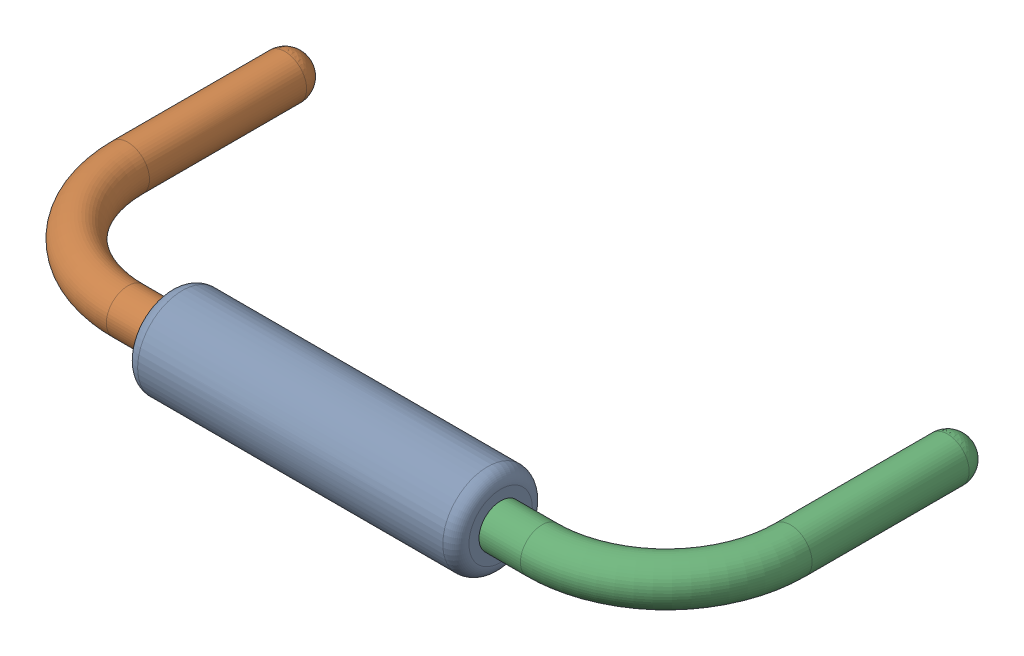
SolidWorks assembly R9, configuration Défaut. Lengths in mm.
Overall size (10.82 1.37 5.33).
4 component instances, 3 part files, 0 mates.
Components (placement in the parent):
- Open CASCADE STEP translator 6.8 1.10.1-1: Open CASCADE STEP translator 6.8 1.10.1 [Défaut] at origin size (10.82 1.37 5.33)
  - Body_1_7-1: Body_1_7 [Défaut] at origin size (5.08 1.37 1.37)
  - Pin_1_4-1: Pin_1_4 [Défaut] at origin size (3.2 0.66 4.98)
  - Pin_2_4-1: Pin_2_4 [Défaut] at (20.32 0 0) x (-1 0 0) z (0 0 1) size (3.2 0.66 4.98)
